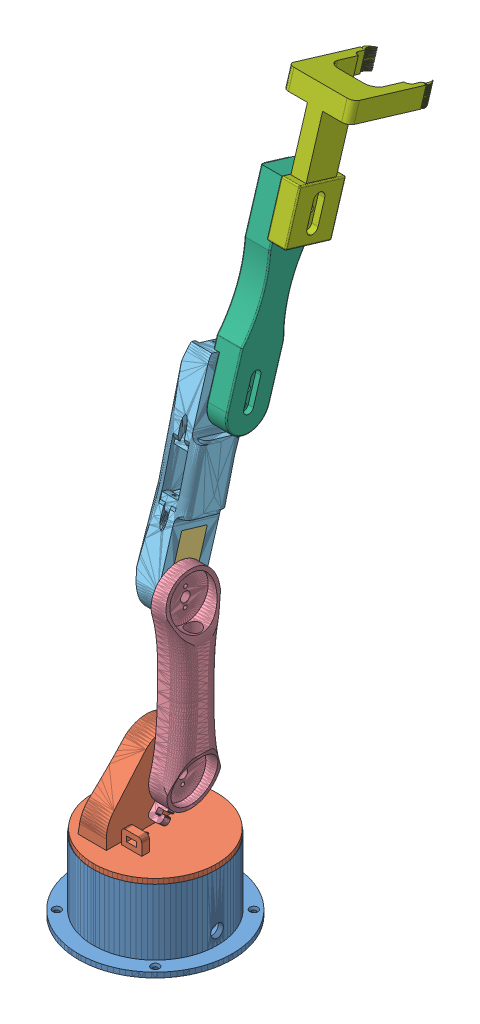
SolidWorks assembly Assem1, configuration Default. Lengths in mm.
Overall size (121.24 525.69 238.57).
10 component instances, 7 part files, 24 mates.
Components (placement in the parent):
- base0-1: base0 [Default] at (48.9065 45.2888 96.9938) size (121.24 56 121.25)
- waist0-1: waist0 [Default] at (46.3326 89.214 97.2003) x (0.999993 0 0.003863) z (-0.003863 0 0.999993) size (96.99 64.78 97)
- cube-1: cube [Default] at (26.8725 96.3222 97.6088) x (0.002731 0.707107 -0.707102) z (0.999993 0 0.003863) size (41 21 12)
- Arm 01-1: Arm 01 [Default] at (48.4906 117.8274 77.8452) x (0.003862 -0.015869 -0.999867) z (0.999993 0 0.003863) size (43.22 166.68 21)
- Arm 02-1: Arm 02 [Default] at (42.4842 246.1928 71.0978) x (-0.999904 0.005507 0.012694) z (-0.013732 -0.281887 -0.959349) size (27.46 167.91 39.33)
- cube-3: cube [Default] at (30.5438 233.133 63.9198) x (0.001704 0.959432 -0.281936) z (0.999992 -0.000585 0.004053) size (41 21 12)
- cube-4: cube [Default] at (40.7914 377.8036 22.4885) x (-0.001704 -0.959432 0.281936) z (-0.999992 0.000585 -0.004053) size (41 21 12)
- The new arm-2: The new arm [Default] at (38.6604 356.8374 52.6609) x (-0.000238 -0.288245 -0.957557) z (0.999999 -0.001615 0.000238) size (35.06 162.5 20.12)
- cube-5: cube [Default] at (36.8908 492.0671 2.3116) x (-0.001615 -0.957555 0.288245) z (0.999999 -0.001615 0.000238) size (41 21 12)
-   End Effector 01-1:   End Effector 01 [Default] at (72.8241 448.1367 -15.4201) x (0.000238 0.288245 0.957557) z (-0.999999 0.001615 -0.000238) size (76.5 100 52)
Mates (geometry in assembly coordinates):
- Parallel1: parallel aligned: plane of base0-1 through (48.9065 85.214 96.9938) normal (0 1 0); plane of waist0-1 through (46.3326 89.214 97.2003) normal (0 1 0)
- Coincident2: coincident: plane of base0-1 through (48.9065 85.214 96.9938) normal (0 1 0); line of waist0-1 through (94.8729 85.214 95.2529) axis (-0.072325 0 -0.997381)
- Coincident3: coincident: line of base0-1 through (94.7743 85.214 100.8738) axis (0.049595 0 -0.998769); plane of waist0-1 through (94.7599 85.214 101.1653) normal (0.998769 0 0.049595)
- Parallel4: parallel aligned: plane of base0-1 through (48.9065 85.214 96.9938) normal (0 1 0); plane of waist0-1 through (46.3326 89.214 97.2003) normal (0 1 0)
- Coincident8: coincident anti-aligned: plane of waist0-1 through (40.4139 96.3222 97.6611) normal (0.002731 0.707107 -0.707102); plane of cube-1 through (38.8724 96.3222 97.6551) normal (-0.002731 -0.707107 0.707102)
- Coincident9: coincident: plane of waist0-1 through (40.3566 111.1714 112.5102) normal (0.002731 -0.707107 -0.707101); line of cube-1 through (26.9271 140.1628 83.4667) axis (-0.002731 -0.707107 0.707102)
- Parallel5: parallel: plane of waist0-1 through (42.4158 89.214 97.1852) normal (0.999993 0 0.003863); line of Arm 01-1 through (42.4944 121.4328 76.8321) axis (-0.003842 0.10295 0.994679)
- Coincident12: coincident: plane of waist0-1 through (-1.99 125.4903 74.1782) normal (-0.003853 -0.071333 0.997445); line of Arm 01-1 through (42.506 118.3431 73.8389) axis (0.000276 -0.997453 -0.071333)
- Coincident13: coincident: line of waist0-1 through (42.4759 149.9294 81.6229) axis (-0.003861 0.027752 0.999607); plane of Arm 01-1 through (42.4906 117.8274 77.822) normal (-0.999993 0 -0.003863)
- Coincident20: coincident aligned: plane of Arm 01-1 through (48.4503 120.8476 88.1235) normal (0.003764 -0.281919 -0.959431); plane of Arm 02-1 through (42.5559 240.8294 52.845) normal (0.003764 -0.281919 -0.959431)
- Coincident21: coincident: plane of Arm 01-1 through (42.4906 117.8274 77.822) normal (-0.999993 0 -0.003863); line of Arm 02-1 through (42.483 248.4579 79.7872) axis (-0.000849 -0.975549 0.219781)
- Coincident25: coincident anti-aligned: line of Arm 02-1 through (29.4602 239.0543 84.0636) axis (0.999992 -0.000585 0.004053); line of cube-3 through (42.4655 239.0467 84.1164) axis (-0.999992 0.000585 -0.004053)
- Coincident28: coincident: point of Arm 01-1; plane of cube-3 through (42.5437 233.1259 63.9684) normal (0.999992 -0.000585 0.004053)
- Coincident29: coincident anti-aligned: plane of Arm 02-1 through (42.6529 341.151 43.1937) normal (0.001704 0.959432 -0.281936); plane of cube-4 through (28.7217 338.4739 33.9993) normal (-0.001704 -0.959432 0.281936)
- Coincident30: coincident anti-aligned: plane of Arm 02-1 through (42.4415 249.4283 82.1079) normal (0.003724 -0.281941 -0.959425); plane of cube-4 through (28.7133 383.7313 42.5878) normal (-0.003724 0.281941 0.959425)
- Coincident31: coincident: unknown of Arm 02-1; plane of cube-4 through (40.7914 377.8036 22.4885) normal (0.999992 -0.000585 0.004053)
- Coincident32: coincident anti-aligned: plane of Arm 02-1 through (42.714 382.4113 30.0931) normal (0.001615 0.957555 -0.288245); plane of The new arm-2 through (42.7022 376.4266 10.2117) normal (-0.001615 -0.957555 0.288245)
- Tangent1: tangent anti-aligned: plane of Arm 02-1 through (42.5174 246.1928 71.0979) normal (0.999992 -0.000579 0.004071); torus of The new arm-2
- Coincident43: coincident anti-aligned: plane of The new arm-2 through (48.8857 485.9178 -18.0495) normal (-0.001615 -0.957555 0.288245); plane of cube-5 through (48.8908 492.0478 2.3145) normal (0.001615 0.957555 -0.288245)
- Coincident44: coincident anti-aligned: line of The new arm-2 through (48.8229 451.8304 14.4207) axis (0.001615 0.957555 -0.288245); line of cube-5 through (48.8908 492.0478 2.3145) axis (-0.001615 -0.957555 0.288245)
- Concentric1: concentric anti-aligned: cylinder of The new arm-2 through (58.9386 481.3061 -5.5592) axis (-0.999999 0.001615 -0.000238) radius 6; circle of   End Effector 01-1
- Parallel17: parallel anti-aligned: line of The new arm-2 through (58.8849 484.8928 -21.3986) axis (0.000238 0.288245 0.957557); line of   End Effector 01-1 through (77.4581 496.1391 8.769) axis (-0.000238 -0.288245 -0.957557)
- Parallel18: parallel aligned: plane of The new arm-2 through (58.6604 356.8051 52.6656) normal (0.999999 -0.001615 0.000238); plane of cube-5 through (48.8908 492.0478 2.3145) normal (0.999999 -0.001615 0.000238)
- Coincident47: coincident: line of The new arm-2 through (57.8862 485.5637 -22.6446) axis (-0.001615 -0.957555 0.288245); plane of   End Effector 01-1 through (57.8241 448.161 -15.4237) normal (-0.999999 0.001615 -0.000238)
